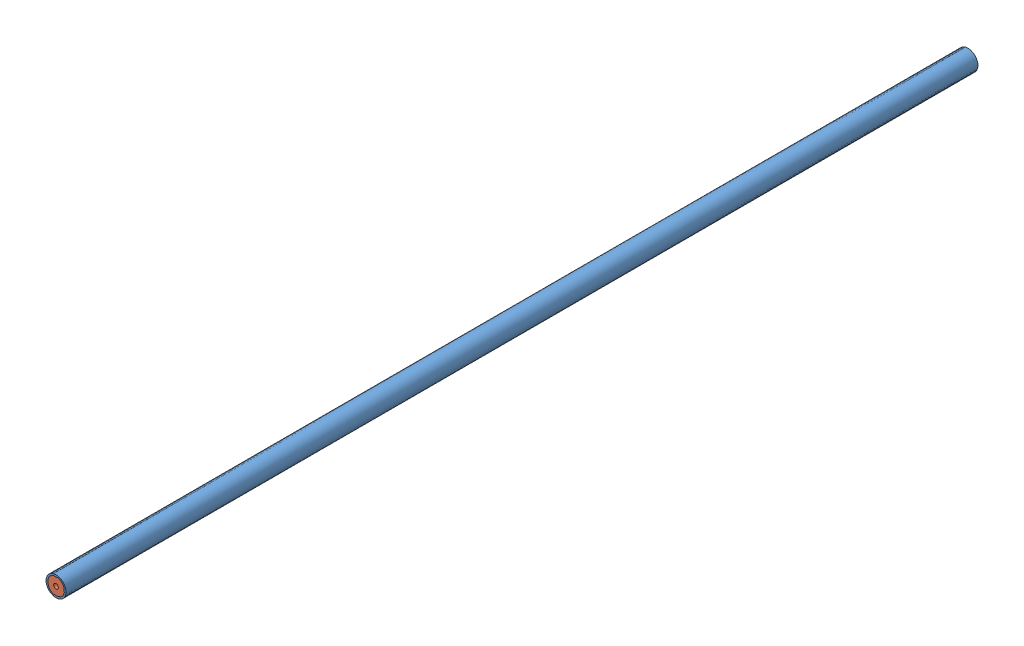
SolidWorks assembly ТП.016.03.06.00 - Штанга связки, configuration 00. Lengths in mm.
Overall size (21.43 21.43 971.2).
3 component instances, 2 part files, 9 mates.
Components (placement in the parent):
- ТП.016.03.06.01 - Труба связка-1: ТП.016.03.06.01 - Труба связка [--] at (0 0 489.6) size (21.3 21.3 971.2)
- ТП.016.03.06.02 - Втулка штанги-1: ТП.016.03.06.02 - Втулка штанги [--] at (198.0992 0 485.6) size (18 18 30)
- ТП.016.03.06.02 - Втулка штанги-2: ТП.016.03.06.02 - Втулка штанги [--] at (216.8746 2.0316 -485.6) x (-0.976855 -0.213903 0) z (0 0 -1) size (18 18 30)
Mates (geometry in assembly coordinates):
- Симметричный1: symmetric: plane of ТП.016.03.06.01 - Труба связка-1 through (208.7492 -10.65 485.6) normal (0 0 1); plane of ТП.016.03.06.01 - Труба связка-1 through (208.7492 -10.65 -485.6) normal (0 0 -1); plane of assembly
- Совпадение2: coincident: plane of ТП.016.03.06.01 - Труба связка-1 through (0 0 489.6) normal (0 1 0); plane of assembly through (0 0 0) normal (0 1 0)
- Совпадение3: coincident: plane of ТП.016.03.06.01 - Труба связка-1 through (0 0 489.6) normal (1 0 0); plane of assembly through (0 0 0) normal (1 0 0)
- Совпадение4: coincident: plane of ТП.016.03.06.01 - Труба связка-1 through (208.7492 -10.65 485.6) normal (0 0 1); plane of ТП.016.03.06.02 - Втулка штанги-1 through (198.0992 0 485.6) normal (0 0 1)
- Параллельность1: parallel: plane of ТП.016.03.06.01 - Труба связка-1 through (0 0 489.6) normal (0 1 0); plane of ТП.016.03.06.02 - Втулка штанги-1 through (198.0992 0 485.6) normal (0 1 0)
- Касательность1: tangent: cylinder of ТП.016.03.06.01 - Труба связка-1 through (208.7492 -10.65 -30.1227) axis (0 0 1) radius 10.65; plane of ТП.016.03.06.02 - Втулка штанги-1 through (198.0992 0 485.6) normal (0 1 0)
- Касательность2: tangent: cylinder of ТП.016.03.06.01 - Труба связка-1 through (208.7492 -10.65 -30.1227) axis (0 0 1) radius 10.65; plane of ТП.016.03.06.02 - Втулка штанги-1 through (198.0992 0 485.6) normal (1 0 0)
- Концентричный1: concentric: cylinder of ТП.016.03.06.01 - Труба связка-1 through (208.7492 -10.65 -30.1227) axis (0 0 1) radius 8.65; cylinder of ТП.016.03.06.02 - Втулка штанги-2 through (208.7492 -10.65 -455.6) axis (0 0 -1) radius 9
- Совпадение5: coincident: plane of ТП.016.03.06.01 - Труба связка-1 through (208.7492 -10.65 -485.6) normal (0 0 -1); plane of ТП.016.03.06.02 - Втулка штанги-2 through (208.7492 -10.65 -485.6) normal (0 0 -1)
